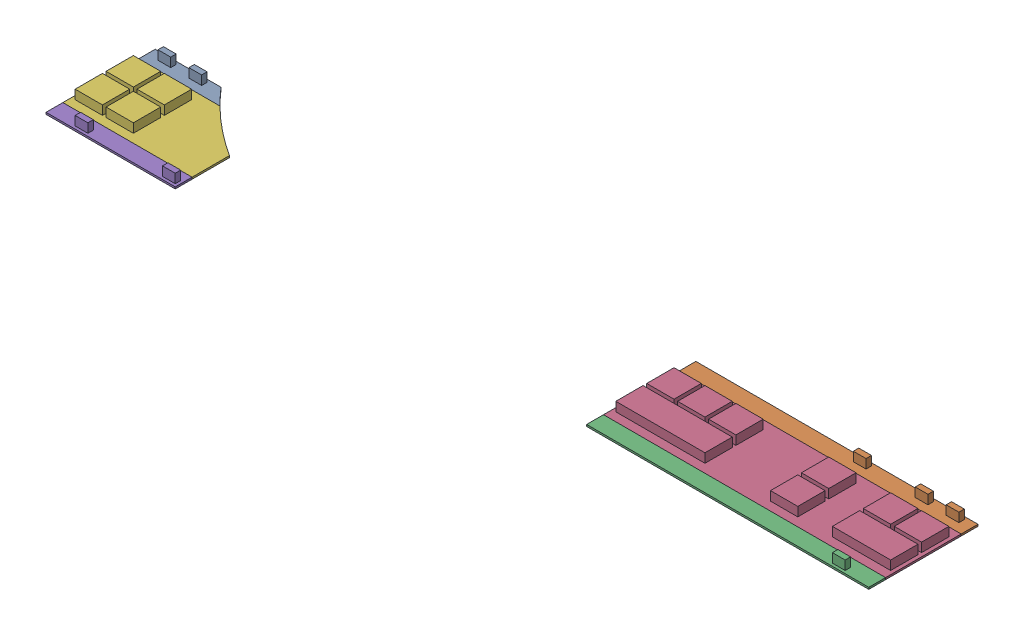
SolidWorks assembly 02_Controls, configuration Default. Lengths in mm.
Overall size (452 6 60).
6 component instances, 6 part files, 0 mates.
Components (placement in the parent):
- Controls_B.1-1: Controls_B.1 [Default] at (0 -6 0) size (44.81 6 9.25)
- Controls_B.3-1: Controls_B.3 [Default] at (0 -6 0) size (155 6 9.25)
- Controls_B.4-1: Controls_B.4 [Default] at (0 -6 0) size (155 6 9.25)
- Controls_A.2-1: Controls_A.2 [Default] at (0 -6 0) size (155 6 41.5)
- Controls_B.2-1: Controls_B.2 [Default] at (0 -6 0) size (71 6 9.25)
- Controls_A.1-1: Controls_A.1 [Default] at (0 -6 0) size (71 6 41.5)
